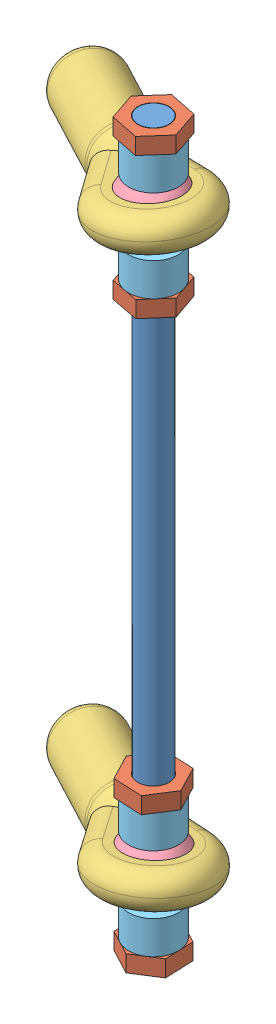
SolidWorks assembly elbow, configuration Default. Lengths in mm.
Overall size (27.61 69.85 22.59).
15 component instances, 5 part files, 21 mates.
Components (placement in the parent):
- elbow_rod-1: elbow_rod [Default] at (-9.1612 -25.5522 3.8591) size (2.95 69.85 2.95)
- 4-40_nut-2: 4-40_nut [Default] at (-9.1612 42.7103 3.8591) x (-0.979813 0 -0.199916) z (0.199916 0 -0.979813) size (5.5 1.59 4.76)
- balljoint-1: balljoint [Default] at (-19.4065 34.972 -4.9557) x (-0.845118 -0.145212 -0.514479) z (-0.516683 -0.025052 0.85581) size (25.24 6.88 10.32) (flexible)
  - balljoint_joint-1: balljoint_joint [Default] at (-6.0674 0.1484 2.2064) size (25.24 5.95 10.32)
  - balljoint_ball-2: balljoint_ball [Default] at (-13.4478 0.1484 2.2064) x (-0.48591 0.09335 -0.86901) z (-0.861861 0.114018 0.494161) size (6.35 5.63 6.35)
- 4-40_spacer-1: 4-40_spacer [Default] at (-9.1612 39.5353 3.8591) x (-0.637207 0 0.770693) z (-0.770693 0 -0.637207) size (4.76 3.17 4.76)
- 4-40_spacer-2: 4-40_spacer [Default] at (-9.1612 30.7353 3.8591) x (-0.584041 0 -0.811724) z (0.811724 0 -0.584041) size (4.76 3.17 4.76)
- 4-40_spacer-4: 4-40_spacer [Default] at (-9.1612 -23.9647 3.8591) x (0.755343 0 -0.655329) z (0.655329 0 0.755343) size (4.76 3.17 4.76)
- 4-40_spacer-5: 4-40_spacer [Default] at (-9.1612 -15.1646 3.8591) x (0.985018 0 0.172451) z (-0.172451 0 0.985018) size (4.76 3.17 4.76)
- 4-40_nut-4: 4-40_nut [Default] at (-9.1612 -25.5522 3.8591) x (0.846047 0 -0.533109) z (0.533109 0 0.846047) size (5.5 1.59 4.76)
- balljoint-2: balljoint [Default] at (-21.6732 -19.9523 -1.169) x (-0.845118 -0.145212 -0.514479) z (0.526204 -0.05628 -0.848494) size (25.24 6.83 10.32) (flexible)
  - balljoint_joint-1: balljoint_joint [Default] at (-6.0674 0.1484 2.2064) size (25.24 5.95 10.32)
  - balljoint_ball-2: balljoint_ball [Default] at (-13.4478 0.1484 2.2064) x (-0.01421 0.054795 0.998397) z (-0.989299 -0.145779 -0.006079) size (6.35 5.63 6.35)
- 4-40_nut-5: 4-40_nut [Default] at (-9.1612 29.1478 3.8591) x (0.327031 0 0.945013) z (-0.945013 0 0.327031) size (5.5 1.59 4.76)
- 4-40_nut-6: 4-40_nut [Default] at (-9.1612 -11.9896 3.8591) x (0.998976 0 0.045234) z (-0.045234 0 0.998976) size (5.5 1.59 4.76)
Mates (geometry in assembly coordinates):
- Concentric1: concentric aligned: circle of elbow_rod-1; circle of 4-40_nut-2
- Coincident1: coincident aligned: plane of elbow_rod-1 through (-9.1612 44.2978 3.8591) normal (0 1 0); plane of 4-40_nut-2 through (-10.9843 44.2978 5.9174) normal (0 1 0)
- Concentric6: concentric aligned: cylinder of elbow_rod-1 through (-9.1612 44.2978 3.8591) axis (0 -1 0) radius 1.4732; cylinder of 4-40_spacer-1 through (-9.1612 42.7103 3.8591) axis (0 -1 0) radius 1.4605
- Coincident4: coincident anti-aligned: plane of 4-40_nut-2 through (-10.9843 42.7103 5.9174) normal (0 -1 0); plane of 4-40_spacer-1 through (-9.1612 42.7103 3.8591) normal (0 1 0)
- Concentric8: concentric aligned: cylinder of elbow_rod-1 through (-9.1612 44.2978 3.8591) axis (0 -1 0) radius 1.4732; cylinder of 4-40_nut-4 through (-9.1612 -23.9647 3.8591) axis (0 -1 0) radius 1.4986
- Coincident8: coincident aligned: plane of elbow_rod-1 through (-9.1612 -25.5522 3.8591) normal (0 -1 0); plane of 4-40_nut-4 through (-9.2675 -25.5522 1.1115) normal (0 -1 0)
- Coincident9: coincident anti-aligned: plane of 4-40_spacer-4 through (-9.1612 -23.9647 3.8591) normal (0 -1 0); plane of 4-40_nut-4 through (-9.2675 -23.9647 1.1115) normal (0 1 0)
- Concentric9: concentric aligned: cylinder of elbow_rod-1 through (-9.1612 44.2978 3.8591) axis (0 -1 0) radius 1.4732; cylinder of 4-40_spacer-4 through (-9.1612 -20.7897 3.8591) axis (0 -1 0) radius 1.4605
- Parallel1: parallel aligned: cylinder of balljoint-1/balljoint_joint-1 through (824.7085 180.002 511.4901) axis (0.845118 0.145212 0.514479) radius 2.9766; cylinder of balljoint-2/balljoint_joint-1 through (824.7085 125.3021 511.4901) axis (0.845118 0.145212 0.514479) radius 2.9766
- Concentric15: concentric aligned: cylinder of elbow_rod-1 through (-9.1612 44.2978 3.8591) axis (0 -1 0) radius 1.4732; cylinder of 4-40_nut-5 through (-9.1612 30.7353 3.8591) axis (0 -1 0) radius 1.4986
- Concentric16: concentric aligned: cylinder of elbow_rod-1 through (-9.1612 44.2978 3.8591) axis (0 -1 0) radius 1.4732; cylinder of 4-40_nut-6 through (-9.1612 -10.4021 3.8591) axis (0 -1 0) radius 1.4986
- Coincident17: coincident anti-aligned: plane of 4-40_spacer-5 through (-9.1612 -11.9896 3.8591) normal (0 1 0); plane of 4-40_nut-6 through (-7.6801 -11.9896 1.5425) normal (0 -1 0)
- Coincident18: coincident anti-aligned: plane of 4-40_spacer-2 through (-9.1612 30.7353 3.8591) normal (0 -1 0); plane of 4-40_nut-5 through (-6.4613 30.7353 4.3796) normal (0 1 0)
- Coincident21: coincident aligned: circle of balljoint-1/balljoint_ball-2; plane of 4-40_spacer-1 through (-9.1612 39.5353 3.8591) normal (0 -1 0)
- Coincident22: coincident anti-aligned: circle of balljoint-1/balljoint_ball-2; plane of 4-40_spacer-2 through (-9.1612 33.9103 3.8591) normal (0 1 0)
- Coincident23: coincident anti-aligned: plane of 4-40_spacer-4 through (-9.1612 -20.7897 3.8591) normal (0 1 0); circle of balljoint-2/balljoint_ball-2
- Coincident24: coincident aligned: plane of 4-40_spacer-5 through (-9.1612 -15.1646 3.8591) normal (0 -1 0); circle of balljoint-2/balljoint_ball-2
- Concentric18: concentric aligned: cylinder of elbow_rod-1 through (-9.1612 44.2978 3.8591) axis (0 -1 0) radius 1.4732; cylinder of balljoint-1/balljoint_ball-2 through (-9.1612 -963.2772 3.8591) axis (0 -1 0) radius 1.4732
- Concentric19: concentric aligned: cylinder of elbow_rod-1 through (-9.1612 44.2978 3.8591) axis (0 -1 0) radius 1.4732; cylinder of balljoint-2/balljoint_ball-2 through (-9.1612 -1017.9772 3.8591) axis (0 -1 0) radius 1.4732
- Concentric20: concentric aligned: cylinder of elbow_rod-1 through (-9.1612 44.2978 3.8591) axis (0 -1 0) radius 1.4732; cylinder of 4-40_spacer-5 through (-9.1612 -11.9896 3.8591) axis (0 -1 0) radius 1.4605
- Concentric21: concentric aligned: cylinder of elbow_rod-1 through (-9.1612 44.2978 3.8591) axis (0 -1 0) radius 1.4732; cylinder of 4-40_spacer-2 through (-9.1612 33.9103 3.8591) axis (0 -1 0) radius 1.4605
